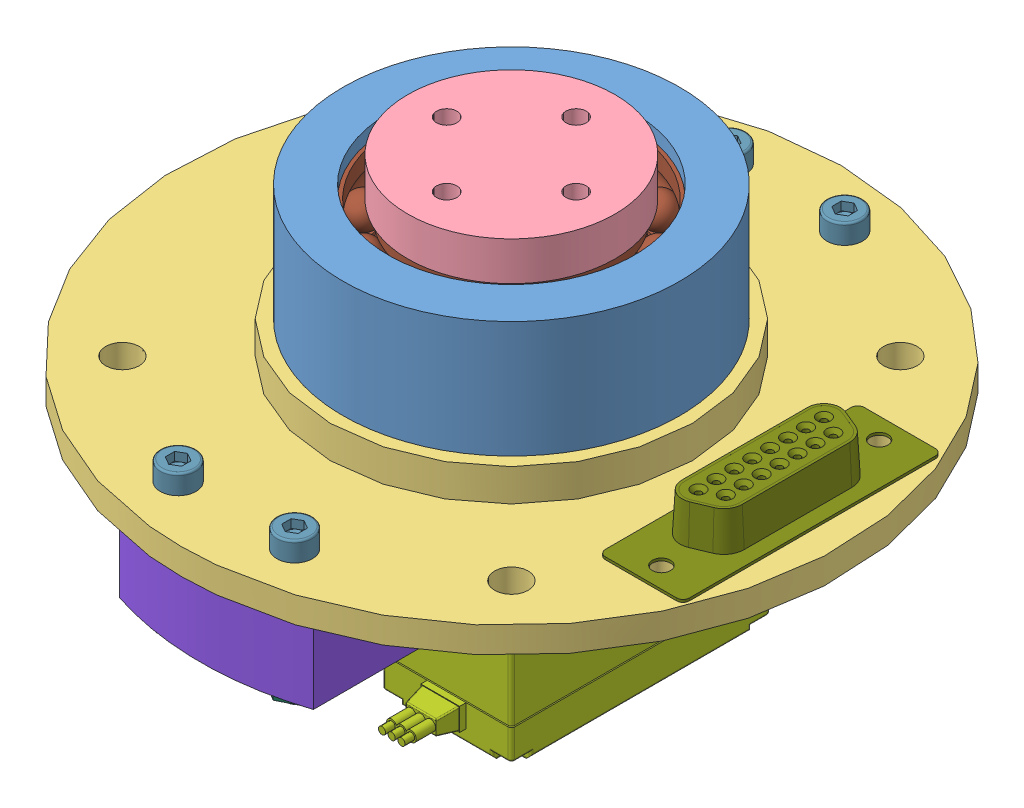
SolidWorks assembly link_0, configuration По умолчанию. Lengths in mm.
Overall size (102 73 102).
38 component instances, 16 part files, 49 mates.
Components (placement in the parent):
- shell_0-2: shell_0 [По умолчанию] x (-1 0 0) z (0 -1 0) size (52 52 23)
- sleave_external_0-1: sleave_external_0 [00] at (0 12 0) x (0 -1 0) z (0.129917 0 0.991525) size (3 42 42)
- flange_0-1: flange_0 [По умолчанию] at (0 -4 0) size (102 9 102)
- shaft_0-1: shaft_0 [00] at (0 -4 0) x (0 -1 0) z (0 0 -1) size (31 32 32)
- servo_flange-1: servo_flange [По умолчанию] at (0 -1.5 0) x (-0.707107 0 0.707107) z (0.707107 0 0.707107) size (20 4.5 20)
- screw_M3x8(DIN912)-1: screw_M3x8(DIN912) [По умолчанию] at (4.9497 -6 4.9497) x (-0.866025 0 -0.5) z (0 -1 0) size (4.6 4.6 10)
- screw_M3x8(DIN912)-2: screw_M3x8(DIN912) [По умолчанию] at (-4.9497 -6 4.9497) x (0.5 0 -0.866025) z (0 -1 0) size (4.6 4.6 10)
- screw_M3x8(DIN912)-3: screw_M3x8(DIN912) [По умолчанию] at (-4.9497 -6 -4.9497) x (0.866025 0 0.5) z (0 -1 0) size (4.6 4.6 10)
- screw_M3x8(DIN912)-4: screw_M3x8(DIN912) [По умолчанию] at (4.9497 -6 -4.9497) x (-0.5 0 0.866025) z (0 -1 0) size (4.6 4.6 10)
- servo_MG995-1: servo_MG995 [По умолчанию] at (0 -46 -10) x (0 0 1) z (0 1 0) size (55.5 20 44.57)
- servo_lock-1: servo_lock [По умолчанию] at (0 -17 0) x (-1 0 0) z (0 0 -1) size (30 13 96)
- screw_M4x14(DIN912)-1: screw_M4x14(DIN912) [По умолчанию] at (5 -23 14) x (0.91175 0 0.410745) z (0 -1 0) size (7 7 18)
- ГайкаM4(DIN936)-1: ГайкаM4(DIN936) [По умолчанию] at (5 -9 14) size (7 2.2 8.08)
- screw_M4x14(DIN912)-2: screw_M4x14(DIN912) [По умолчанию] at (-5 -23 14) x (0.91175 0 0.410745) z (0 -1 0) size (7 7 18)
- screw_M4x14(DIN912)-3: screw_M4x14(DIN912) [По умолчанию] at (5 -23 -34) x (0.91175 0 0.410745) z (0 -1 0) size (7 7 18)
- screw_M4x14(DIN912)-4: screw_M4x14(DIN912) [По умолчанию] at (-5 -23 -34) x (0.91175 0 0.410745) z (0 -1 0) size (7 7 18)
- ГайкаM4(DIN936)-2: ГайкаM4(DIN936) [По умолчанию] at (-5 -9 14) size (7 2.2 8.08)
- ГайкаM4(DIN936)-3: ГайкаM4(DIN936) [По умолчанию] at (5 -9 -34) size (7 2.2 8.08)
- ГайкаM4(DIN936)-4: ГайкаM4(DIN936) [По умолчанию] at (-5 -9 -34) size (7 2.2 8.08)
- bearing_6905-2RS_0-1: bearing_6905-2RS_0 [00] at (0 21 0) x (0 -1 0) z (-0.000456 0 -1) size (9 42 42)
- sleave_internal_0-1: sleave_internal_0 [00] at (0 12 0) x (0 -1 0) z (0.154614 0 0.987975) size (3 29 29)
- bearing_6905-2RS_0-2: bearing_6905-2RS_0 [00] at (0 9 0) x (0 -1 0) z (-0.000456 0 -1) size (9 42 42)
- circlip for shafts normal_din-1: circlip for shafts normal_din [Circlip DIN 471 - 25 x 1.2] x (0.999946 0 -0.010391) z (0 1 0) size (28.33 31.3 1.2)
- socket head cap screw_din-1: socket head cap screw_din [DIN 912 M2.5 x 10 --- 10N] at (11.75 -6.5 20.3516) x (0 1 0) z (-0.355215 0 0.934785) size (12.5 4.5 4.5)
- socket head cap screw_din-2: socket head cap screw_din [DIN 912 M2.5 x 10 --- 10N] at (-11.75 -6.5 20.3516) x (0 1 0) z (-0.987155 0 0.159767) size (12.5 4.5 4.5)
- socket head cap screw_din-3: socket head cap screw_din [DIN 912 M2.5 x 10 --- 10N] at (-23.5 -6.5 0) x (0 1 0) z (-0.631939 0 -0.775018) size (12.5 4.5 4.5)
- socket head cap screw_din-4: socket head cap screw_din [DIN 912 M2.5 x 10 --- 10N] at (-11.75 -6.5 -20.3516) x (0 1 0) z (0.355215 0 -0.934785) size (12.5 4.5 4.5)
- socket head cap screw_din-5: socket head cap screw_din [DIN 912 M2.5 x 10 --- 10N] at (11.75 -6.5 -20.3516) x (0 1 0) z (0.987155 0 -0.159767) size (12.5 4.5 4.5)
- socket head cap screw_din-6: socket head cap screw_din [DIN 912 M2.5 x 10 --- 10N] at (23.5 -6.5 0) x (0 1 0) z (0.631939 0 0.775018) size (12.5 4.5 4.5)
- socket head cap screw_din-7: socket head cap screw_din [DIN 912 M3 x 20 --- 20N] at (9 3 42.5) x (0 -1 0) z (1 0 0) size (23 5.5 5.5)
- hex thin nut gradeb_din-1: hex thin nut gradeb_din [Hexagon Nut ISO 4036 - M3 - N] at (9 -18.8 42.5) x (0.546938 0 -0.837173) z (0 -1 0) size (5.5 6.35 1.8)
- socket head cap screw_din-8: socket head cap screw_din [DIN 912 M3 x 20 --- 20N] at (9 3 -42.5) x (0 -1 0) z (1 0 0) size (23 5.5 5.5)
- socket head cap screw_din-9: socket head cap screw_din [DIN 912 M3 x 20 --- 20N] at (-9 3 42.5) x (0 -1 0) z (1 0 0) size (23 5.5 5.5)
- socket head cap screw_din-10: socket head cap screw_din [DIN 912 M3 x 20 --- 20N] at (-9 3 -42.5) x (0 -1 0) z (1 0 0) size (23 5.5 5.5)
- hex thin nut gradeb_din-2: hex thin nut gradeb_din [Hexagon Nut ISO 4036 - M3 - N] at (9 -18.8 -42.5) x (0.546938 0 -0.837173) z (0 -1 0) size (5.5 6.35 1.8)
- hex thin nut gradeb_din-3: hex thin nut gradeb_din [Hexagon Nut ISO 4036 - M3 - N] at (-9 -18.8 42.5) x (0.546938 0 -0.837173) z (0 -1 0) size (5.5 6.35 1.8)
- hex thin nut gradeb_din-4: hex thin nut gradeb_din [Hexagon Nut ISO 4036 - M3 - N] at (-9 -18.8 -42.5) x (0.546938 0 -0.837173) z (0 -1 0) size (5.5 6.35 1.8)
- DB15_F-1: DB15_F [По умолчанию] at (38.6 6.31 9.695) x (0 0 -1) z (1 0 0) size (40 15.72 13)
Mates (geometry in assembly coordinates):
- Совпадение7: coincident anti-aligned: plane of shell_0-2 through (0 0 -21) normal (0 -1 0); plane of flange_0-1 through (0 0 0) normal (0 1 0)
- Концентричный5: concentric anti-aligned: cylinder of shell_0-2 through (-11.75 0 -20.3516) axis (0 -1 0) radius 1.275; cylinder of flange_0-1 through (-11.75 0 -20.3516) axis (0 1 0) radius 1.275
- Концентричный6: concentric anti-aligned: cylinder of shell_0-2 through (11.75 0 20.3516) axis (0 -1 0) radius 1.275; cylinder of flange_0-1 through (11.75 0 20.3516) axis (0 1 0) radius 1.275
- Концентричный8: concentric anti-aligned: cylinder of shell_0-2 through (-11.75 0 20.3516) axis (0 -1 0) radius 1.275; cylinder of ? through (-11.75 6 20.3516) axis (0 1 0) radius 1.5
- Совпадение8: coincident aligned: plane of flange_0-1 through (0 -4 0) normal (0 -1 0); plane of ? through (-11.75 -4 20.3516) normal (0 -1 0)
- Концентричный10: concentric aligned: cylinder of servo_flange-1 through (4.9497 -4 4.9497) axis (0 1 0) radius 1.5; cylinder of screw_M3x8(DIN912)-1 through (4.9497 -6 4.9497) axis (0 1 0) radius 1.5
- Совпадение13: coincident anti-aligned: plane of servo_flange-1 through (0 -4 0) normal (0 -1 0); plane of screw_M3x8(DIN912)-1 through (6.0997 -4 2.9579) normal (0 1 0)
- Концентричный11: concentric anti-aligned: cylinder of servo_flange-1 through (0 -4 0) axis (0 1 0) radius 2.95; cylinder of servo_MG995-1 through (0 -5.2 0) axis (0 -1 0) radius 2
- Совпадение22: coincident anti-aligned: plane of servo_MG995-1 through (-10 -19.3 -29.5) normal (-1 0 0); plane of servo_lock-1 through (-10 -9 -30) normal (1 0 0)
- Совпадение23: coincident anti-aligned: plane of servo_MG995-1 through (-9.5 -16.7 10) normal (0 0 1); plane of servo_lock-1 through (10 -9 10) normal (0 0 -1)
- Совпадение24: coincident anti-aligned: plane of servo_MG995-1 through (0.75 -17 -30.3) normal (0 1 0); plane of servo_lock-1 through (0 -17 0) normal (0 -1 0)
- Совпадение25: coincident aligned: circle of servo_lock-1; cylinder of screw_M4x14(DIN912)-1 through (5 -23 14) axis (0 1 0) radius 2
- Совпадение26: coincident anti-aligned: plane of servo_MG995-1 through (9.5 -19 10.3) normal (0 -1 0); plane of screw_M4x14(DIN912)-1 through (3.5624 -19 17.1911) normal (0 1 0)
- Совпадение27: coincident anti-aligned: plane of servo_lock-1 through (0 -9 0) normal (0 1 0); plane of ГайкаM4(DIN936)-1 through (5 -9 14) normal (0 -1 0)
- Концентричный14: concentric anti-aligned: cylinder of screw_M4x14(DIN912)-1 through (5 -23 14) axis (0 1 0) radius 2; circle of ГайкаM4(DIN936)-1
- Концентричный15: concentric aligned: cylinder of flange_0-1 through (-9 -4 42.5) axis (0 -1 0) radius 1.575; cylinder of ? through (-9 3 42.5) axis (0 -1 0) radius 1.5
- Совпадение28: coincident anti-aligned: plane of flange_0-1 through (0 0 0) normal (0 1 0); plane of ? through (-9.2501 0 44.9875) normal (0 -1 0)
- Концентричный16: concentric aligned: cylinder of shaft_0-1 through (0 -4 0) axis (0 1 0) radius 12.5; cylinder of bearing_6905-2RS_0-1 through (0 21 0) axis (0 1 0) radius 12.5
- Совпадение29: coincident anti-aligned: plane of shaft_0-1 through (-12.5 21 0) normal (0 -1 0); plane of bearing_6905-2RS_0-1 through (-15.05 21 0.0069) normal (0 1 0)
- Концентричный17: concentric aligned: cylinder of sleave_external_0-1 through (0 12 0) axis (0 1 0) radius 19; cylinder of shaft_0-1 through (0 -4 0) axis (0 1 0) radius 12.5
- Совпадение30: coincident anti-aligned: plane of sleave_external_0-1 through (20.822 12 -2.7282) normal (0 1 0); plane of bearing_6905-2RS_0-1 through (-18.45 12 0.0084) normal (0 -1 0)
- Совпадение31: coincident aligned: cylinder of shaft_0-1 through (0 -4 0) axis (0 1 0) radius 12.5; circle of sleave_internal_0-1
- Совпадение32: coincident anti-aligned: plane of bearing_6905-2RS_0-1 through (-12.5 12 0.0057) normal (0 -1 0); plane of sleave_internal_0-1 through (14.3256 12 -2.2419) normal (0 1 0)
- Концентричный18: concentric aligned: cylinder of shaft_0-1 through (0 -4 0) axis (0 1 0) radius 12.5; cylinder of bearing_6905-2RS_0-2 through (0 9 0) axis (0 1 0) radius 12.5
- Совпадение33: coincident anti-aligned: plane of sleave_internal_0-1 through (12.3497 9 -1.9327) normal (0 -1 0); plane of bearing_6905-2RS_0-2 through (-15.05 9 0.0069) normal (0 1 0)
- Концентричный19: concentric anti-aligned: cylinder of shell_0-2 through (0 0 0) axis (0 -1 0) radius 21; cylinder of bearing_6905-2RS_0-1 through (0 21 0) axis (0 1 0) radius 21
- Концентричный20: concentric anti-aligned: cylinder of shaft_0-1 through (0 -4 0) axis (0 -1 0) radius 10; cylinder of servo_flange-1 through (0 -4 0) axis (0 1 0) radius 10
- Концентричный21: concentric anti-aligned: cylinder of shaft_0-1 through (4.9497 -4 4.9497) axis (0 -1 0) radius 1.5; cylinder of screw_M3x8(DIN912)-1 through (4.9497 -6 4.9497) axis (0 1 0) radius 1.5
- Совпадение34: coincident anti-aligned: plane of shaft_0-1 through (-10 -1.5 0) normal (0 -1 0); plane of servo_flange-1 through (0 -1.5 0) normal (0 1 0)
- Концентричный22: concentric anti-aligned: cylinder of servo_flange-1 through (0 -6 0) axis (0 1 0) radius 4.5; cylinder of servo_MG995-1 through (0 -5.2 0) axis (0 -1 0) radius 2
- Совпадение36: coincident anti-aligned: plane of flange_0-1 through (0 -4 0) normal (0 -1 0); plane of servo_lock-1 through (0 -4 0) normal (0 1 0)
- Совпадение38: coincident anti-aligned: plane of shell_0-2 through (0 21 -19) normal (0 -1 0); plane of bearing_6905-2RS_0-1 through (-21 21 0.0096) normal (0 1 0)
- Совпадение41: coincident anti-aligned: plane of bearing_6905-2RS_0-2 through (-12.5 0 0.0057) normal (0 -1 0); plane of circlip for shafts normal_din-1 through (0 0 0) normal (0 1 0)
- Концентричный24: concentric anti-aligned: cylinder of shaft_0-1 through (0 -4 0) axis (0 -1 0) radius 11.95; cylinder of circlip for shafts normal_din-1 through (0 -1.2 0) axis (0 1 0) radius 11.95
- Угол1: planar angle = 3.141593 rad aligned: plane of shaft_0-1 through (0 -4 0) normal (-1 0 0); plane of assembly through (0 0 0) normal (1 0 0)
- Концентричный27: concentric anti-aligned: cylinder of flange_0-1 through (11.75 0 20.3516) axis (0 1 0) radius 1.275; cylinder of socket head cap screw_din-1 through (11.75 -38.25 20.3516) axis (0 -1 0) radius 1.25
- Совпадение42: coincident anti-aligned: plane of flange_0-1 through (0 -4 0) normal (0 -1 0); plane of socket head cap screw_din-1 through (9.6467 -4 19.5524) normal (0 1 0)
- Концентричный28: concentric anti-aligned: cylinder of flange_0-1 through (9 -4 42.5) axis (0 -1 0) radius 1.575; cylinder of socket head cap screw_din-7 through (9 34.75 42.5) axis (0 1 0) radius 1.5
- Совпадение43: coincident anti-aligned: plane of flange_0-1 through (0 0 0) normal (0 1 0); plane of socket head cap screw_din-7 through (9 0 39.75) normal (0 -1 0)
- Концентричный29: concentric anti-aligned: cylinder of socket head cap screw_din-7 through (9 34.75 42.5) axis (0 1 0) radius 1.5; circle of hex thin nut gradeb_din-1
- Совпадение44: coincident anti-aligned: plane of servo_lock-1 through (0 -17 0) normal (0 -1 0); plane of hex thin nut gradeb_din-1 through (11.6584 -17 44.2368) normal (0 1 0)
- Концентричный30: concentric anti-aligned: cylinder of flange_0-1 through (-9 -4 42.5) axis (0 -1 0) radius 1.575; cylinder of servo_lock-1 through (-9 -4 42.5) axis (0 1 0) radius 1.575
- Совпадение45: coincident anti-aligned: plane of flange_0-1 through (0 0 0) normal (0 1 0); plane of DB15_F-1 through (45.52 0 -19) normal (0 -1 0)
- Концентричный31: concentric anti-aligned: cylinder of flange_0-1 through (40 -4 -16.82) axis (0 1 0) radius 1.5; cylinder of DB15_F-1 through (40 6.31 -16.82) axis (0 -1 0) radius 1.4
- Концентричный32: concentric anti-aligned: cylinder of flange_0-1 through (40 -4 16.82) axis (0 1 0) radius 1.5; cylinder of DB15_F-1 through (40 6.31 16.82) axis (0 -1 0) radius 1.4
- Концентричный33: concentric aligned: cylinder of flange_0-1 through (0 0 0) axis (0 -1 0) radius 51; cylinder of servo_lock-1 through (0 -9 0) axis (0 -1 0) radius 48
- Параллельность1: parallel anti-aligned: line of socket head cap screw_din-9 through (-10.26 3 41.7725) axis (0 0 1); line of DB15_F-1 through (33.52 0.4 19) axis (0 0 -1)
- Параллельность2: parallel aligned: line of screw_M3x8(DIN912)-1 through (6.1997 -6 4.2281) axis (0 0 1); line of servo_MG995-1 through (9.1464 -45.8536 -26.8536) axis (0 0 1)
- Совпадение48: coincident aligned: axis of bearing_6905-2RS_0-1 through (-0.0076 14.7679 -16.75) axis (0 1 0); axis of bearing_6905-2RS_0-2 through (-0.0076 2.7679 -16.75) axis (0 1 0)
